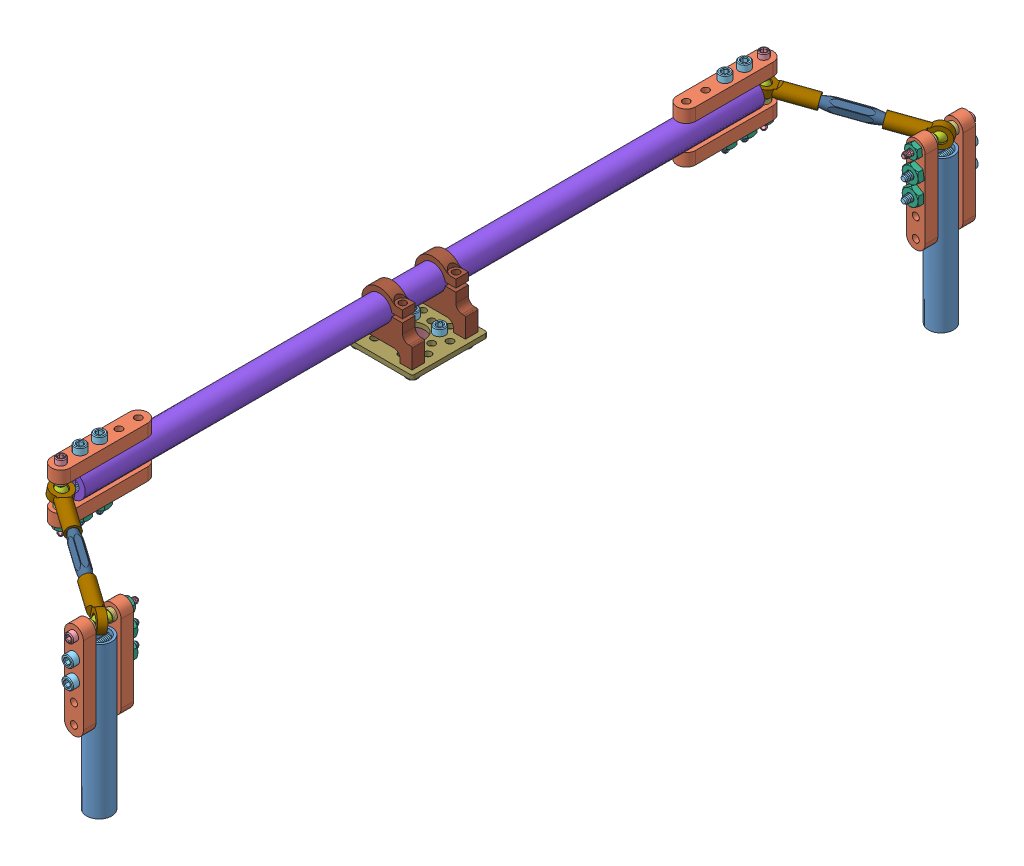
SolidWorks assembly Differential Pivot Assembly, configuration Default. Lengths in mm.
Overall size (81.35 110.21 457.37).
90 component instances, 13 part files, 15 mates.
Components (placement in the parent):
- Diff Pivot Bottom-1: Diff Pivot Bottom [Default] at (99.1475 -103.2326 -114.2495) x (0 0 -1) z (0 1 0) size (35.29 12.7 86.93)
  - 3 inch Aluminum Rod-1: 3 inch Aluminum Rod [Default] at (25.2275 39.993 -257.4677) size (12.7 12.7 76.2)
  - 5 Hole Aluminum Beam-1: 5 Hole Aluminum Beam [Default] at (37.9275 39.993 84.5433) x (0 0 -1) z (0 1 0) size (48.64 6.35 9.53)
  - 5 Hole Aluminum Beam-2: 5 Hole Aluminum Beam [Default] at (18.8775 39.993 84.5433) x (0 0 -1) z (0 1 0) size (48.64 6.35 9.53)
  - 4-40 Washer-1: 4-40 Washer [Default] at (18.8775 39.993 104.1013) x (0 -1 0) z (0 0 1) size (5.71 0.71 5.71)
  - 4-40 Washer-2: 4-40 Washer [Default] at (19.5887 39.993 104.1013) x (0 -1 0) z (0 0 1) size (5.71 0.71 5.71)
  - 4-40 Washer-3: 4-40 Washer [Default] at (20.2999 39.993 104.1013) x (0 -1 0) z (0 0 1) size (5.71 0.71 5.71)
  - 4-40 Washer-4: 4-40 Washer [Default] at (29.4439 39.993 104.1013) x (0 -1 0) z (0 0 1) size (5.71 0.71 5.71)
  - 4-40 Washer-5: 4-40 Washer [Default] at (30.1551 39.993 104.1013) x (0 -1 0) z (0 0 1) size (5.71 0.71 5.71)
  - 4-40 Washer-6: 4-40 Washer [Default] at (30.8663 39.993 104.1013) x (0 -1 0) z (0 0 1) size (5.71 0.71 5.71)
  - 4-40_SHCS-1: 4-40_SHCS [4-40 SHCS X 1.250] at (6.1775 39.993 104.1013) x (0 0.924225 0.381849) z (1 0 0) size (4.65 4.65 34.63)
  - 6-32_SHCS-1: 6-32_SHCS [6-32 SHCS X 1.250] at (6.1775 39.993 94.3223) x (0 0 -1) z (1 0 0) size (5.74 5.74 35.26)
  - 6-32_SHCS-2: 6-32_SHCS [6-32 SHCS X 1.250] at (6.1775 39.993 84.5433) x (0 0 -1) z (1 0 0) size (5.74 5.74 35.26)
  - hex_nut-2: hex_nut [#4-40] at (12.5275 39.993 104.1013) x (0 0.381849 -0.924225) z (0 0.924225 0.381849) size (6.35 2.49 8.06)
  - hex_nut-3: hex_nut [#6-32] at (12.5275 39.993 94.3223) x (0 0.381849 -0.924225) z (0 0.924225 0.381849) size (7.92 2.9 10.06)
  - hex_nut-4: hex_nut [#6-32] at (12.5275 39.993 84.5433) x (0 1 0) z (0 0 1) size (7.92 2.9 10.06)
  - Ball bearing-1: Ball bearing [Default] at (21.1 39.993 104.1013) x (0 -1 0) z (0 0 1) size (5.73 8.26 5.73)
- Diff Pivot Bottom-2: Diff Pivot Bottom [Default] at (19.1615 -103.2326 260.2571) x (0 0 1) z (0 1 0) size (35.29 12.7 86.93)
  - 3 inch Aluminum Rod-1: 3 inch Aluminum Rod [Default] at (25.2275 39.993 -257.4677) size (12.7 12.7 76.2)
  - 5 Hole Aluminum Beam-1: 5 Hole Aluminum Beam [Default] at (37.9275 39.993 84.5433) x (0 0 -1) z (0 1 0) size (48.64 6.35 9.53)
  - 5 Hole Aluminum Beam-2: 5 Hole Aluminum Beam [Default] at (18.8775 39.993 84.5433) x (0 0 -1) z (0 1 0) size (48.64 6.35 9.53)
  - 4-40 Washer-1: 4-40 Washer [Default] at (18.8775 39.993 104.1013) x (0 -1 0) z (0 0 1) size (5.71 0.71 5.71)
  - 4-40 Washer-2: 4-40 Washer [Default] at (19.5887 39.993 104.1013) x (0 -1 0) z (0 0 1) size (5.71 0.71 5.71)
  - 4-40 Washer-3: 4-40 Washer [Default] at (20.2999 39.993 104.1013) x (0 -1 0) z (0 0 1) size (5.71 0.71 5.71)
  - 4-40 Washer-4: 4-40 Washer [Default] at (29.4439 39.993 104.1013) x (0 -1 0) z (0 0 1) size (5.71 0.71 5.71)
  - 4-40 Washer-5: 4-40 Washer [Default] at (30.1551 39.993 104.1013) x (0 -1 0) z (0 0 1) size (5.71 0.71 5.71)
  - 4-40 Washer-6: 4-40 Washer [Default] at (30.8663 39.993 104.1013) x (0 -1 0) z (0 0 1) size (5.71 0.71 5.71)
  - 4-40_SHCS-1: 4-40_SHCS [4-40 SHCS X 1.250] at (6.1775 39.993 104.1013) x (0 0.924225 0.381849) z (1 0 0) size (4.65 4.65 34.63)
  - 6-32_SHCS-1: 6-32_SHCS [6-32 SHCS X 1.250] at (6.1775 39.993 94.3223) x (0 0 -1) z (1 0 0) size (5.74 5.74 35.26)
  - 6-32_SHCS-2: 6-32_SHCS [6-32 SHCS X 1.250] at (6.1775 39.993 84.5433) x (0 0 -1) z (1 0 0) size (5.74 5.74 35.26)
  - hex_nut-2: hex_nut [#4-40] at (12.5275 39.993 104.1013) x (0 0.381849 -0.924225) z (0 0.924225 0.381849) size (6.35 2.49 8.06)
  - hex_nut-3: hex_nut [#6-32] at (12.5275 39.993 94.3223) x (0 0.381849 -0.924225) z (0 0.924225 0.381849) size (7.92 2.9 10.06)
  - hex_nut-4: hex_nut [#6-32] at (12.5275 39.993 84.5433) x (0 1 0) z (0 0 1) size (7.92 2.9 10.06)
  - Ball bearing-1: Ball bearing [Default] at (21.1 39.993 104.1013) x (0 -1 0) z (0 0 1) size (5.73 8.26 5.73)
- Diff Pivot Top-1: Diff Pivot Top [Default] at (-159.2548 -99.818 354.5171) x (0 1 0) z (0 0 -1) size (35.29 12.7 364.36)
  - 13.5 Inch Aluminum Rod-1: 13.5 Inch Aluminum Rod [Default] at (112.518 164.0173 110.0632) size (12.7 12.7 342.9)
  - 5 Hole Aluminum Beam-1: 5 Hole Aluminum Beam [Default] at (106.168 164.0173 439.3742) x (0 0 -1) z (0 1 0) size (48.64 6.35 9.53)
  - 5 Hole Aluminum Beam-2: 5 Hole Aluminum Beam [Default] at (125.218 164.0173 439.3742) x (0 0 -1) z (0 1 0) size (48.64 6.35 9.53)
  - 6-32_SHCS-1: 6-32_SHCS [6-32 SHCS X 1.250] at (93.468 164.0173 449.1532) x (0 0 -1) z (1 0 0) size (5.74 5.74 35.26)
  - 6-32_SHCS-2: 6-32_SHCS [6-32 SHCS X 1.250] at (93.468 164.0173 439.3742) x (0 0 -1) z (1 0 0) size (5.74 5.74 35.26)
  - 4-40_SHCS-1: 4-40_SHCS [4-40 SHCS X 1.250] at (93.468 164.0173 458.9322) x (0 -0.924225 -0.381849) z (1 0 0) size (4.65 4.65 34.63)
  - 4-40 Washer-1: 4-40 Washer [Default] at (118.1568 164.0173 458.9322) x (0 -1 0) z (0 0 1) size (5.71 0.71 5.71)
  - 4-40 Washer-2: 4-40 Washer [Default] at (118.1568 164.0173 458.9322) x (0 1 0) z (0 0 1) size (5.71 0.71 5.71)
  - 4-40 Washer-3: 4-40 Washer [Default] at (116.7344 164.0173 458.9322) x (0 -1 0) z (0 0 1) size (5.71 0.71 5.71)
  - 4-40 Washer-4: 4-40 Washer [Default] at (106.168 164.0173 458.9322) x (0 -1 0) z (0 0 1) size (5.71 0.71 5.71)
  - 4-40 Washer-5: 4-40 Washer [Default] at (107.5904 164.0173 458.9322) x (0 -1 0) z (0 0 1) size (5.71 0.71 5.71)
  - 4-40 Washer-6: 4-40 Washer [Default] at (106.8792 164.0173 458.9322) x (0 -1 0) z (0 0 1) size (5.71 0.71 5.71)
  - hex_nut-1: hex_nut [#6-32] at (99.818 164.0173 449.1532) x (0 1 0) z (0 0 1) size (7.92 2.9 10.06)
  - hex_nut-2: hex_nut [#6-32] at (99.818 164.0173 439.3742) x (0 0.381849 -0.924225) z (0 0.924225 0.381849) size (7.92 2.9 10.06)
  - hex_nut-3: hex_nut [#4-40] at (99.818 164.0173 458.9322) x (0 -0.381849 0.924225) z (0 -0.924225 -0.381849) size (6.35 2.49 8.06)
  - 5 Hole Aluminum Beam-3: 5 Hole Aluminum Beam [Default] at (99.818 164.0173 123.6522) x (0 0 1) z (0 1 0) size (48.64 6.35 9.53)
  - 5 Hole Aluminum Beam-4: 5 Hole Aluminum Beam [Default] at (118.868 164.0173 123.6522) x (0 0 1) z (0 1 0) size (48.64 6.35 9.53)
  - 6-32_SHCS-3: 6-32_SHCS [6-32 SHCS X 1.250] at (93.468 164.0173 113.8732) x (0 0 -1) z (1 0 0) size (5.74 5.74 35.26)
  - 6-32_SHCS-4: 6-32_SHCS [6-32 SHCS X 1.250] at (93.468 164.0173 123.6522) x (0 0 -1) z (1 0 0) size (5.74 5.74 35.26)
  - 4-40_SHCS-2: 4-40_SHCS [4-40 SHCS X 1.250] at (93.468 164.0173 104.0942) x (0 0.924225 -0.381849) z (1 0 0) size (4.65 4.65 34.63)
  - 4-40 Washer-7: 4-40 Washer [Default] at (118.1568 164.0173 104.0942) x (0 -1 0) z (0 0 1) size (5.71 0.71 5.71)
  - 4-40 Washer-8: 4-40 Washer [Default] at (118.1568 164.0173 104.0942) x (0 1 0) z (0 0 1) size (5.71 0.71 5.71)
  - 4-40 Washer-9: 4-40 Washer [Default] at (116.7344 164.0173 104.0942) x (0 -1 0) z (0 0 1) size (5.71 0.71 5.71)
  - 4-40 Washer-10: 4-40 Washer [Default] at (106.168 164.0173 104.0942) x (0 -1 0) z (0 0 1) size (5.71 0.71 5.71)
  - 4-40 Washer-11: 4-40 Washer [Default] at (107.5904 164.0173 104.0942) x (0 -1 0) z (0 0 1) size (5.71 0.71 5.71)
  - 4-40 Washer-12: 4-40 Washer [Default] at (106.8792 164.0173 104.0942) x (0 -1 0) z (0 0 1) size (5.71 0.71 5.71)
  - hex_nut-4: hex_nut [#6-32] at (99.818 164.0173 113.8732) x (0 1 0) z (0 0 1) size (7.92 2.9 10.06)
  - hex_nut-5: hex_nut [#4-40] at (99.818 164.0173 104.0942) x (0 -0.381849 -0.924225) z (0 0.924225 -0.381849) size (6.35 2.49 8.06)
  - hex_nut-6: hex_nut [#6-32] at (99.818 164.0173 123.6522) x (0 0.381849 0.924225) z (0 -0.924225 0.381849) size (7.92 2.9 10.06)
  - Ball bearing-1: Ball bearing [Default] at (116.6455 164.0173 458.9322) x (0 1 0) z (0 0 1) size (5.73 8.26 5.73)
  - Ball bearing-2: Ball bearing [Default] at (108.3905 164.0173 104.0942) x (0 -1 0) z (0 0 1) size (5.73 8.26 5.73)
- Turnbuckle-1: Turnbuckle [Default] at (11.2495 13.9339 281.7054) x (-0.206532 -0.978391 -0.009752) z (0.523204 -0.102012 -0.84608) size (10.16 75.95 10.16)
  - Turnbuckle Eyes-1: Turnbuckle Eyes [Default] at (2.8521 0.9861 23.1995) size (6.86 25.91 10.16)
  - Turnbuckle screw-1: Turnbuckle screw [Default] at (2.8521 -11.0789 23.1995) x (0.535456 0 0.844563) z (-0.844563 0 0.535456) size (5.85 35.56 6.83)
  - Turnbuckle Eyes-2: Turnbuckle Eyes [Default] at (2.8521 -23.1439 23.1995) x (0 0 1) z (1 0 0) size (6.86 25.91 10.16)
- Turnbuckle-2: Turnbuckle [Default] at (36.2767 -18.0743 -127.6459) x (0.54433 0.016981 0.838699) z (0.141785 0.983548 -0.111935) size (10.16 75.95 10.16)
  - Turnbuckle Eyes-1: Turnbuckle Eyes [Default] at (2.8521 0.9861 23.1995) size (6.86 25.91 10.16)
  - Turnbuckle screw-1: Turnbuckle screw [Default] at (2.8521 -11.0789 23.1995) x (0.535456 0 0.844563) z (-0.844563 0 0.535456) size (5.85 35.56 6.83)
  - Turnbuckle Eyes-2: Turnbuckle Eyes [Default] at (2.8521 -23.1439 23.1995) x (0 0 1) z (1 0 0) size (6.86 25.91 10.16)
- Diff Pivot Swivel-1: Diff Pivot Swivel [Default] at (9.5463 37.908 36.489) x (1 0 0) z (0 -1 0) size (38.1 38.1 37.32)
  - 0.5 Bore Bottom Tapped Clamping Mount-1: 0.5 Bore Bottom Tapped Clamping Mount [Default] at (101.5047 -5.8505 -6.031) size (33.02 6.35 28.05)
    - 585546-1: 585546 [Default] at (-106.2884 25.7199 31.239) size (33.02 6.35 28.05)
  - 0.5 Bore Bottom Tapped Clamping Mount-2: 0.5 Bore Bottom Tapped Clamping Mount [Default] at (101.5047 21.0903 -6.031) size (33.02 6.35 28.05)
    - 585546-1: 585546 [Default] at (-106.2884 25.7199 31.239) size (33.02 6.35 28.05)
  - 1 Hole Pattern Bracket-1: 1 Hole Pattern Bracket [Default] at (-4.7838 36.5148 46.544) x (1 0 0) z (0 1 0) size (38.1 2.29 38.1)
  - 0.5 Bore Side Tapped Clamping Hub-1: 0.5 Bore Side Tapped Clamping Hub [Default] at (-17.841 70.0403 34.8585) x (0 1 0) z (1 0 0) size (20.57 7.21 26.29)
    - 545600-1: 545600 [Default] at (-33.5255 9.1455 13.0572) size (20.57 7.21 26.29)
  - 6-32_SHCS-2: 6-32_SHCS [6-32 SHCS X .250] at (8.6866 49.9852 40.194) size (5.74 5.74 9.86)
  - 6-32_SHCS-4: 6-32_SHCS [6-32 SHCS X .250] at (2.131 29.6 50.608) x (0.923728 0.383049 0) z (0 0 -1) size (5.74 5.74 9.86)
  - 6-32_SHCS-5: 6-32_SHCS [6-32 SHCS X .250] at (-11.6986 29.6 50.608) x (0.383049 -0.923728 0) z (0 0 -1) size (5.74 5.74 9.86)
  - 6-32_SHCS-6: 6-32_SHCS [6-32 SHCS X .250] at (-11.6986 43.4296 50.608) x (-0.923728 -0.383049 0) z (0 0 -1) size (5.74 5.74 9.86)
  - 6-32_SHCS-7: 6-32_SHCS [6-32 SHCS X .250] at (2.131 43.4296 50.608) x (-0.383049 0.923728 0) z (0 0 -1) size (5.74 5.74 9.86)
  - 6-32_SHCS-8: 6-32_SHCS [6-32 SHCS X .250] at (8.6866 23.0444 40.194) x (0 -1 0) z (0 0 1) size (5.74 5.74 9.86)
  - 6-32_SHCS-9: 6-32_SHCS [6-32 SHCS X .250] at (-18.2542 23.0444 40.194) x (-1 0 0) z (0 0 1) size (5.74 5.74 9.86)
  - 6-32_SHCS-10: 6-32_SHCS [6-32 SHCS X .250] at (-18.2542 49.9852 40.194) x (0 1 0) z (0 0 1) size (5.74 5.74 9.86)
Mates (geometry in assembly coordinates):
- Coincident2: coincident: point of Diff Pivot Top-1; point of Turnbuckle-1/Turnbuckle Eyes-1
- Coincident3: coincident: point of Diff Pivot Bottom-2/Ball bearing-1; point of Turnbuckle-1/Turnbuckle Eyes-2
- Coincident4: coincident: point of Diff Pivot Bottom-1/Ball bearing-1; point of Turnbuckle-2/Turnbuckle Eyes-1
- Coincident5: coincident: point of Diff Pivot Top-1; point of Turnbuckle-2/Turnbuckle Eyes-2
- Parallel1: parallel aligned: plane of Diff Pivot Bottom-1/3 inch Aluminum Rod-1 through (34.591 -81.3003 -133.1269) normal (0 -1 0); plane of Diff Pivot Bottom-2/3 inch Aluminum Rod-1 through (83.718 -81.3003 279.1346) normal (0 -1 0)
- Parallel2: parallel anti-aligned: plane of Diff Pivot Bottom-1/3 inch Aluminum Rod-1 through (34.591 -81.3003 -133.1269) normal (0 -1 0); plane of assembly through (0 0 0) normal (0 1 0)
- Parallel3: parallel aligned: plane of Diff Pivot Bottom-1/3 inch Aluminum Rod-1 through (34.591 -81.3003 -133.1269) normal (0 -1 0); plane of Diff Pivot Top-1/5 Hole Aluminum Beam-1 through (4.7625 0 -104.4152) normal (0 -1 0)
- Coincident6: coincident anti-aligned: plane of Diff Pivot Top-1/5 Hole Aluminum Beam-1 through (4.7625 0 -104.4152) normal (0 -1 0); plane of assembly through (0 0 0) normal (0 1 0)
- Coincident7: coincident anti-aligned: plane of Diff Pivot Top-1/5 Hole Aluminum Beam-2 through (0 19.05 -104.4152) normal (-1 0 0); plane of assembly through (0 0 0) normal (1 0 0)
- Coincident9: coincident aligned: plane of Diff Pivot Bottom-1/3 inch Aluminum Rod-1 through (34.591 -81.3003 -133.1269) normal (0 -1 0); plane of Diff Pivot Bottom-2/3 inch Aluminum Rod-1 through (83.718 -81.3003 279.1346) normal (0 -1 0)
- Parallel5: parallel aligned: plane of Diff Pivot Bottom-2/5 Hole Aluminum Beam-2 through (63.917 0.8687 272.7846) normal (1 0 0); plane of Diff Pivot Top-1/5 Hole Aluminum Beam-3 through (9.525 6.35 250.4228) normal (1 0 0)
- Parallel6: parallel aligned: plane of Diff Pivot Bottom-2/5 Hole Aluminum Beam-2 through (63.917 0.8687 272.7846) normal (1 0 0); plane of Diff Pivot Bottom-1/5 Hole Aluminum Beam-2 through (63.917 0.8687 -126.7769) normal (1 0 0)
- Coincident10: coincident aligned: plane of Diff Pivot Bottom-1/5 Hole Aluminum Beam-2 through (63.917 0.8687 -126.7769) normal (1 0 0); plane of Diff Pivot Bottom-2/5 Hole Aluminum Beam-2 through (63.917 0.8687 272.7846) normal (1 0 0)
- Concentric1: concentric anti-aligned: cylinder of Diff Pivot Top-1/13.5 Inch Aluminum Rod-1 through (4.7625 12.7 -98.4462) axis (0 0 1) radius 6.35; cylinder of Diff Pivot Swivel-1/0.5 Bore Bottom Tapped Clamping Mount-2/585546-1 through (4.7625 12.7 89.6492) axis (0 0 -1) radius 6.35
- Coincident11: coincident anti-aligned: plane of Diff Pivot Top-1 through (-159.2548 -99.818 73.0038) normal (0 0 -1); plane of Diff Pivot Swivel-1 through (9.5463 37.908 73.0038) normal (0 0 1)
